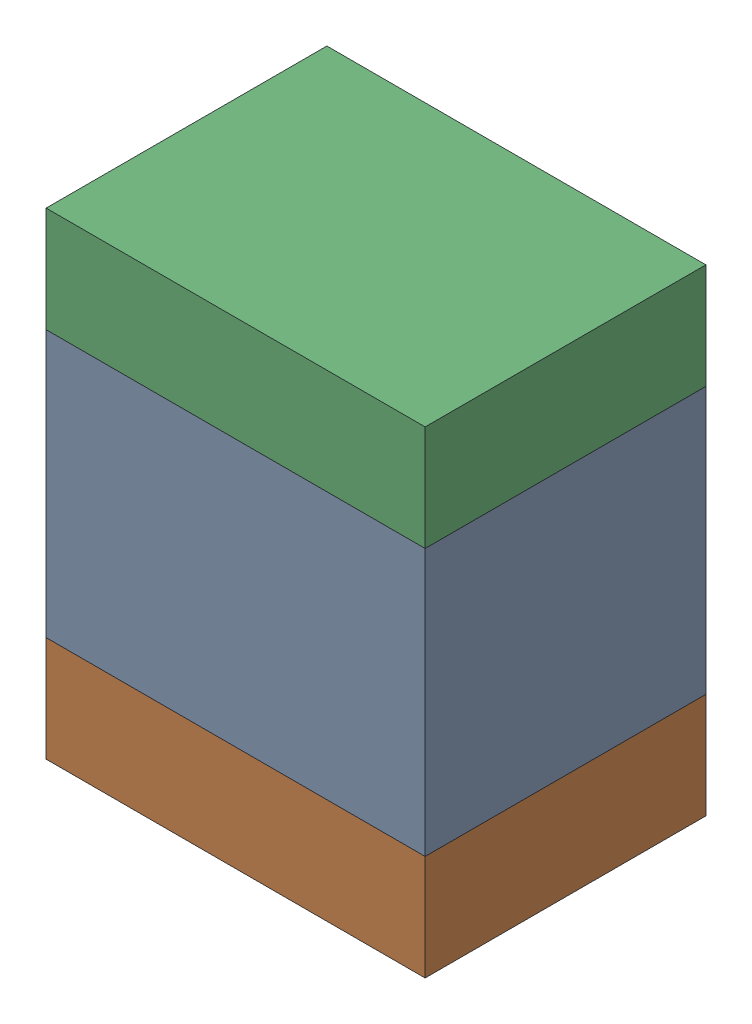
SolidWorks assembly C436PCB, configuration Default. Lengths in mm.
Overall size (2.7 3.4 2).
6 component instances, 2 part files, 0 mates.
Components (placement in the parent):
- 846487504-1: 846487504 [Default] at (84.5 78.475 -3.6638) size (2.7 1.9 2)
  - Extruded_48-1: Extruded_48 [Default] at origin size (2.7 1.9 2)
- 846487640-1: 846487640 [Default] at (84.5 77.15 -3.6638) size (2.7 0.75 2)
  - Extruded_49-1: Extruded_49 [Default] at origin size (2.7 0.75 2)
- 846487640-2: 846487640 [Default] at (84.5 79.8 -3.6638) size (2.7 0.75 2)
  - Extruded_49-1: Extruded_49 [Default] at origin size (2.7 0.75 2)
